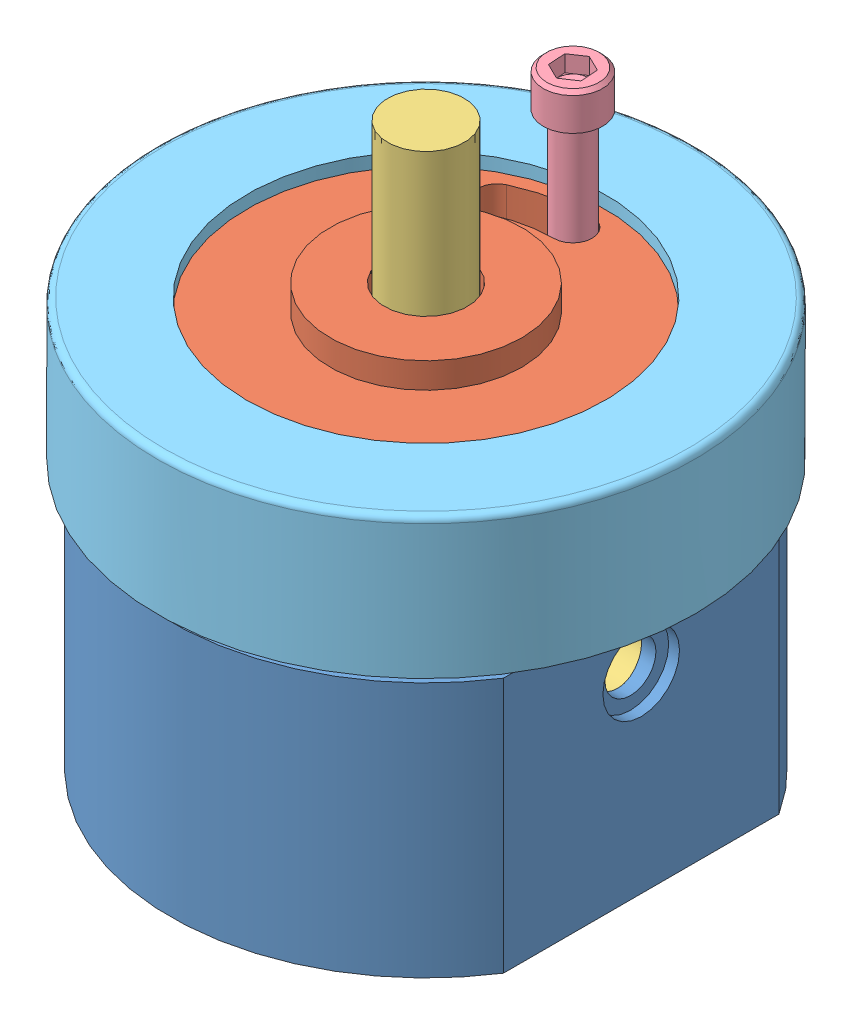
SolidWorks assembly Montagem_Shutter_v8, configuration Valor predeterminado. Lengths in mm.
Overall size (53.16 44 53.16).
5 component instances, 5 part files, 9 mates.
Components (placement in the parent):
- Sede_Inferior_v8-2: Sede_Inferior_v8 [Valor predeterminado<Como usinado>] at origin size (40 26 40)
- Sede_superior_v8-1: Sede_superior_v8 [Valor predeterminado] at (0 2 0) x (0.906308 0 -0.422618) z (0.422618 0 0.906308) size (40 9 40)
- Desviador_v8-1: Desviador_v8 [Valor predeterminado] x (-0.906308 0 -0.422618) z (0.422618 0 -0.906308) size (30 41.5 30)
- socket head cap screw_ai-1: socket head cap screw_ai [HX-SHCS 0.112-48x1x1-N] at (0 26.8448 -11.5) x (0 -1 0) z (0.439394 0 -0.898294) size (28.24 4.65 4.65)
- Fixacao-1: Fixacao [Valor predeterminado] at (0 6 0) x (0.977127 0 -0.212655) z (0.212655 0 0.977127) size (42 11 42)
Mates (geometry in assembly coordinates):
- Coincidente1: coordinate: point of Sede_Inferior_v8-2; point of assembly
- Articulação1: hinge anti-aligned: cylinder of Desviador_v8-1 through (0 0 0) axis (0 -1 0) radius 3; cylinder of Sede_Inferior_v8-2 through (0 0 0) axis (0 -1 0) radius 3.5; plane of Sede_Inferior_v8-2 through (0 -12.5 0) normal (0 1 0); plane of Desviador_v8-1 through (-2.7189 -12.5 -1.2679) normal (0 -1 0)
- Articulação2: hinge anti-aligned: cylinder of Sede_superior_v8-1 through (0 2 0) axis (0 -1 0) radius 3.25; cylinder of Sede_Inferior_v8-2 through (0 0 0) axis (0 -1 0) radius 15; plane of Sede_Inferior_v8-2 through (19.5 11 0) normal (0 1 0); plane of Sede_superior_v8-1 through (4.5315 11 -2.1131) normal (0 -1 0)
- Ranhura4: slot anti-aligned: cylinder of Desviador_v8-1 through (0 -2 -11.5) axis (0 1 0) radius 1.5; cylinder of Sede_superior_v8-1 through (-4.8601 16.001 -10.4225) axis (0 -1 0) radius 1.5; cylinder of Sede_superior_v8-1 through (0 16.001 -11.5) axis (0 -1 0) radius 1.5
- Bloquear11: lock: unknown of Sede_Inferior_v8-2; unknown of Sede_superior_v8-1
- Concêntrico11: concentric aligned: cylinder of Desviador_v8-1 through (0 -2 -11.5) axis (0 1 0) radius 1.5; cylinder of socket head cap screw_ai-1 through (0 58.5948 -11.5) axis (0 1 0) radius 1.4224
- Distância1: distance = 8 mm anti-aligned: plane of socket head cap screw_ai-1 through (-2.0877 24 -12.5212) normal (0 -1 0); plane of Sede_superior_v8-1 through (18.1262 16 -8.4524) normal (0 1 0)
- Concêntrico5: concentric aligned: cylinder of Desviador_v8-1 through (0 0 0) axis (0 -1 0) radius 3; cylinder of Fixacao-1 through (0 6 0) axis (0 -1 0) radius 14
- Coincidente10: coincident anti-aligned: plane of Sede_superior_v8-1 through (18.1262 16 -8.4524) normal (0 1 0); plane of Fixacao-1 through (-13.6798 16 2.9772) normal (0 -1 0)
